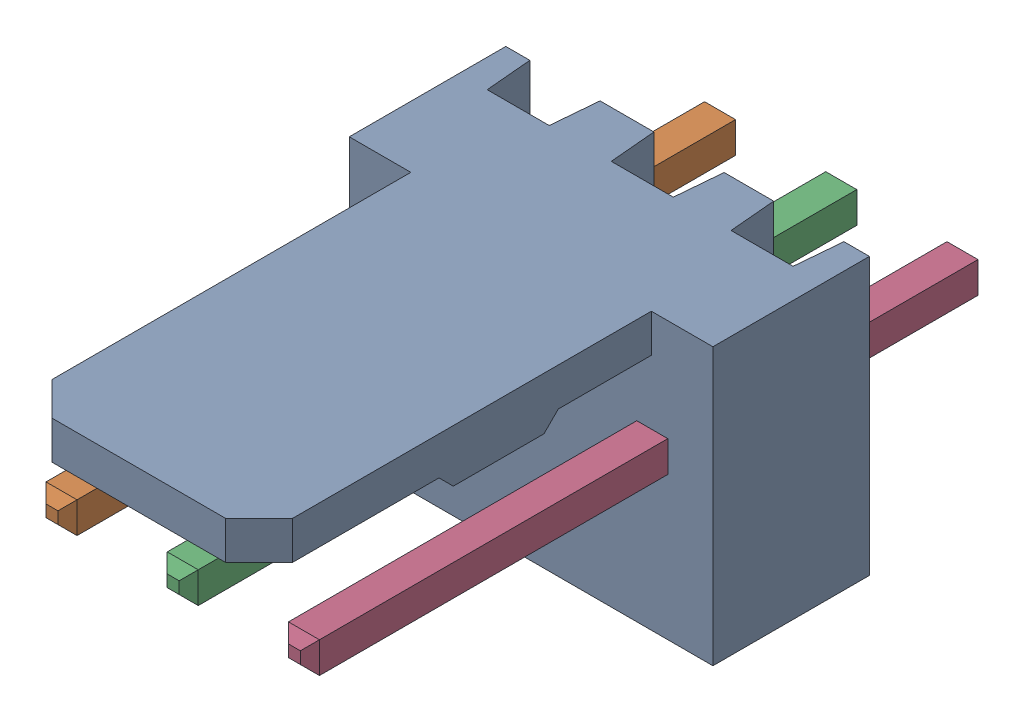
SolidWorks assembly Molex PCB 3 pin v2 v6_1, configuration Default. Lengths in mm.
Overall size (7.62 5.79 14.92).
4 component instances, 2 part files, 0 mates.
Components (placement in the parent):
- BASE9710016 (1)-1: BASE9710016 (1) [Default] at (2.54 2.895 -8.22) size (7.62 5.79 11.5)
- PINO9710016 (1)-1: PINO9710016 (1) [Default] at (1.27 3.325 -0.72) size (0.65 0.65 14.2)
- PINO9710016 (1)-2: PINO9710016 (1) [Default] at (3.81 3.325 -0.72) size (0.65 0.65 14.2)
- PINO9710016 (1)-3: PINO9710016 (1) [Default] at (6.35 3.325 -0.72) size (0.65 0.65 14.2)
